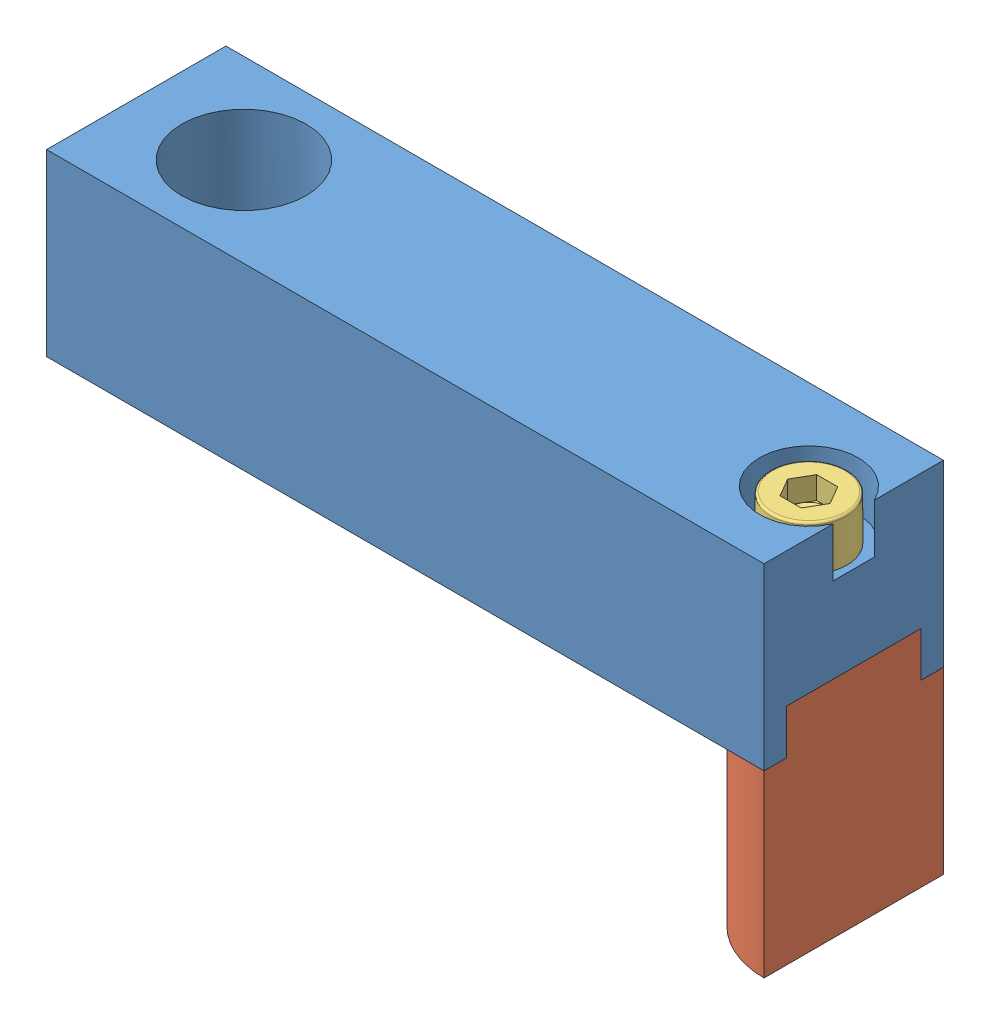
SolidWorks assembly assemb_braco_v1, configuration Default. Lengths in mm.
Overall size (80 40 20).
3 component instances, 3 part files, 5 mates.
Components (placement in the parent):
- clamping_arm_sp_v1-2: clamping_arm_sp_v1 [Default] at (-0.7132 54.1041 61.1653) x (1 0 0) z (0 1 0) size (80 20 20)
- contact_end_half-1: contact_end_half [Default] at (67.2868 14.1041 61.1653) size (10 25 20)
- socket head cap screw_iso-2: socket head cap screw_iso [ISO 4762 M5 x 16 - 16N] at (62.2868 53.6041 61.1653) x (0 -1 0) z (0 0 1) size (21 8.5 8.5)
Mates (geometry in assembly coordinates):
- Concentric1: concentric aligned: cylinder of clamping_arm_sp_v1-2 through (67.2868 39.1041 61.1653) axis (0 -1 0) radius 10; cylinder of contact_end_half-1 through (67.2868 39.1041 61.1653) axis (0 -1 0) radius 10
- Coincident1: coincident aligned: plane of clamping_arm_sp_v1-2 through (67.2868 39.1041 68.6653) normal (1 0 0); plane of contact_end_half-1 through (67.2868 39.1041 51.1653) normal (1 0 0)
- Coincident2: coincident anti-aligned: plane of clamping_arm_sp_v1-2 through (67.2868 39.1041 61.1653) normal (0 -1 0); plane of contact_end_half-1 through (67.2868 39.1041 61.1653) normal (0 1 0)
- Concentric3: concentric anti-aligned: cylinder of clamping_arm_sp_v1-2 through (62.2868 61.8822 61.1653) axis (0 -1 0) radius 2.75; cylinder of socket head cap screw_iso-2 through (62.2868 85.3541 61.1653) axis (0 1 0) radius 4.25
- Coincident4: coincident anti-aligned: plane of clamping_arm_sp_v1-2 through (62.2868 48.6041 61.1653) normal (0 1 0); plane of socket head cap screw_iso-2 through (66.5368 48.6041 61.1653) normal (0 -1 0)
